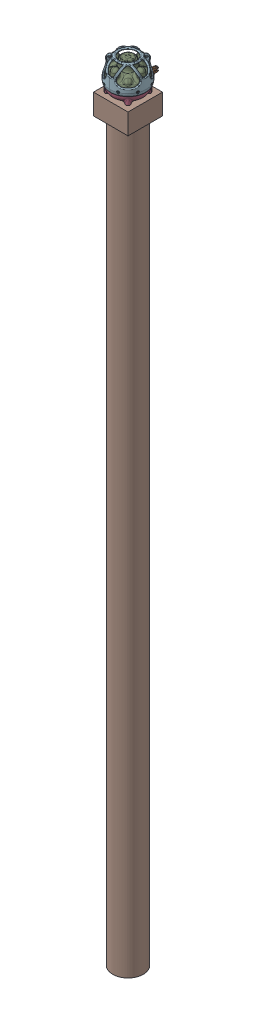
SolidWorks assembly Subsonus_Assembly, configuration Default. Lengths in mm.
Overall size (106.01 2287.02 137.51).
2 component instances, 2 part files, 4 mates.
Components (placement in the parent):
- subsonus-1: subsonus [Default] at (-21.4053 -45.3618 26.1311) size (106.01 93.42 137.51)
- subsonus_mount-1: subsonus_mount [Default] at (-21.4053 -75.3618 26.1311) x (-1 0 0) z (0 0 1) size (100 2193.6 100)
Mates (geometry in assembly coordinates):
- Coincident3: coincident anti-aligned: plane of subsonus-1 through (8.5947 -45.3618 56.1311) normal (0 -1 0); plane of subsonus_mount-1 through (-21.4053 -45.3618 26.1311) normal (0 1 0)
- Parallel2: parallel aligned: plane of subsonus-1 through (-21.4053 -27.3618 -43.8689) normal (0 0 -1); plane of subsonus_mount-1 through (28.5947 -105.3618 -23.8689) normal (0 0 -1)
- Width3: width: plane of subsonus_mount-1 through (28.5947 -105.3618 76.1311) normal (0 0 1); plane of subsonus_mount-1 through (28.5947 -105.3618 -23.8689) normal (0 0 -1); cone of subsonus-1 through (-21.4053 38.6414 26.1311) axis (0 1 0)
- Width4: width: plane of subsonus_mount-1 through (28.5947 -105.3618 -23.8689) normal (1 0 0); plane of subsonus_mount-1 through (-71.4053 -105.3618 -23.8689) normal (-1 0 0); cone of subsonus-1 through (-21.4053 38.6414 26.1311) axis (0 1 0)
